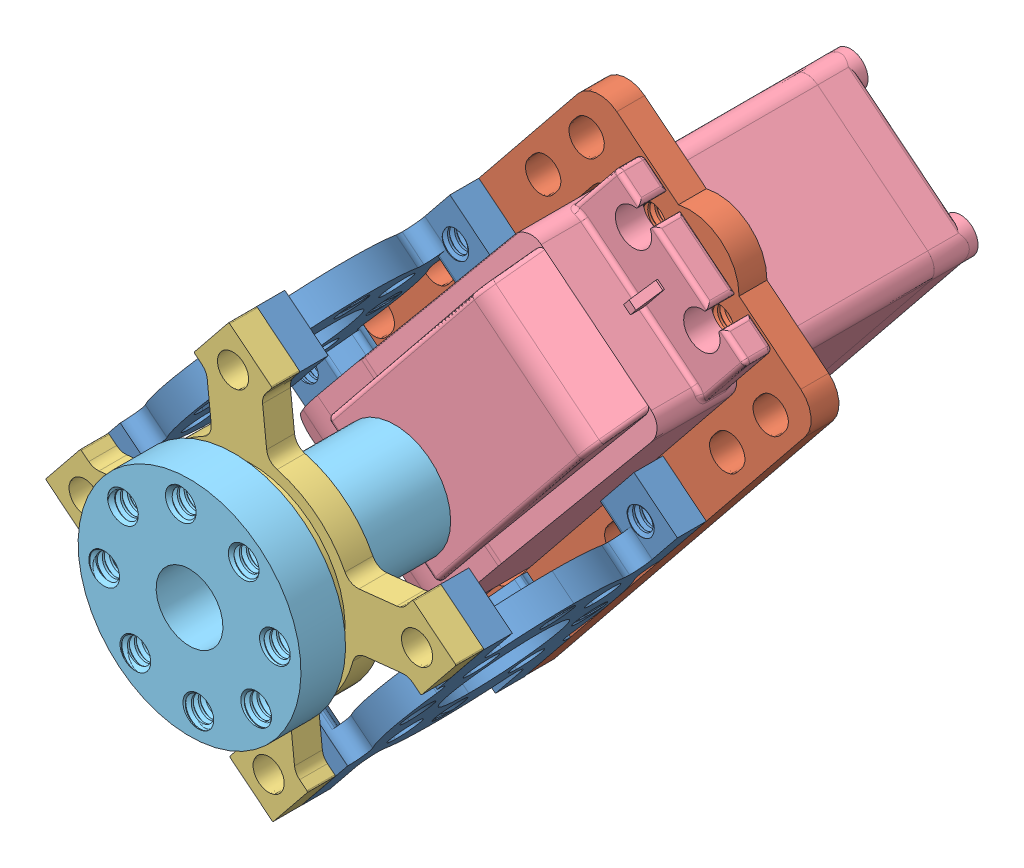
SolidWorks assembly Servo block subassembly, configuration Default. Lengths in mm.
Overall size (64.34 68.55 64.02).
6 component instances, 5 part files, 14 mates.
Components (placement in the parent):
- Side Tapped Pattern Mount A - 545420-1: Side Tapped Pattern Mount A - 545420 [Default] at (442.7678 380.2783 15.875) x (0 0 1) z (0.62777 0.778399 0) size (25.41 6.35 33.02)
- Standard Servo Plate A (575112)-1: Standard Servo Plate A (575112) [Default] at (461.4653 376.9471 0) x (-0.62777 -0.778399 0) z (-0.778399 0.62777 0) size (61.21 3.38 33.29)
- Side Tapped Pattern Mount A - 545420-2: Side Tapped Pattern Mount A - 545420 [Default] at (468.6812 359.3794 15.875) x (0 0 1) z (-0.62777 -0.778399 0) size (25.41 6.35 33.02)
- .5in pillow block-1: .5in pillow block [Default] at (481.7983 354.6785 13.937) x (-0.62777 -0.778399 0) z (-0.778399 0.62777 0) size (33.27 5.09 33.27)
- Servo 20kg elbow and gripper-1: Servo 20kg elbow and gripper [Default] at (462.0715 377.6239 -25.175) x (-0.62777 -0.778399 0) z (-0.778399 0.62777 0) size (55.1 45.65 20.12)
- Servo Hub Shafts 25T (525123)-1: Servo Hub Shafts 25T (525123) [Default] at (455.7245 369.8288 38.735) x (0.99476 0.102238 0) z (-0.102238 0.99476 0) size (25.39 25.51 25.39)
Mates (geometry in assembly coordinates):
- Coincident96: coincident anti-aligned: plane of Side Tapped Pattern Mount A - 545420-1 through (433.3188 387.8988 593.2399) normal (0 0 -1); plane of Standard Servo Plate A (575112)-1 through (441.6486 361.5348 568.1738) normal (0 0 1)
- Concentric109: concentric anti-aligned: circle of Side Tapped Pattern Mount A - 545420-1; cylinder of Standard Servo Plate A (575112)-1 through (433.8788 373.3581 568.2732) axis (0 0 -1) radius 1.778
- Concentric114: concentric anti-aligned: circle of Side Tapped Pattern Mount A - 545420-1; cylinder of .5in pillow block-1 through (453.6955 388.7705 621.8149) axis (0 0 1) radius 1.778
- Coincident101: coincident anti-aligned: plane of Standard Servo Plate A (575112)-1 through (441.6486 361.5348 568.1738) normal (0 0 1); plane of Side Tapped Pattern Mount A - 545420-2 through (478.1302 351.7589 593.2399) normal (0 0 -1)
- Concentric113: concentric aligned: circle of Standard Servo Plate A (575112)-1; circle of Side Tapped Pattern Mount A - 545420-2
- Parallel17: parallel aligned: plane of Standard Servo Plate A (575112)-1 through (454.6047 351.0858 568.1738) normal (0.778399 -0.62777 0); plane of Side Tapped Pattern Mount A - 545420-2 through (468.6812 359.3794 605.9399) normal (0.778399 -0.62777 0)
- Coincident104: coincident anti-aligned: plane of Servo 20kg elbow and gripper-1 through (442.4538 361.2638 593.2399) normal (0 0 -1); plane of Standard Servo Plate A (575112)-1 through (441.6486 361.5348 568.1738) normal (0 0 1)
- Concentric116: concentric anti-aligned: circle of Standard Servo Plate A (575112)-1; cylinder of Servo 20kg elbow and gripper-1 through (442.4538 361.2638 593.2399) axis (0 0 1) radius 2.075
- Parallel18: parallel aligned: plane of Standard Servo Plate A (575112)-1 through (454.6047 351.0858 568.1738) normal (0.778399 -0.62777 0); plane of Servo 20kg elbow and gripper-1 through (457.3076 355.7079 605.3899) normal (0.778399 -0.62777 0)
- Coincident103: coincident anti-aligned: plane of Side Tapped Pattern Mount A - 545420-2 through (478.1302 351.7589 618.6399) normal (0 0 1); plane of .5in pillow block-1 through (455.7245 369.8288 618.6399) normal (0 0 -1)
- Concentric115: concentric anti-aligned: circle of Side Tapped Pattern Mount A - 545420-2; circle of .5in pillow block-1
- Concentric119: concentric anti-aligned: cylinder of .5in pillow block-1 through (455.7245 369.8288 623.7263) axis (0 0 -1) radius 6.35; circle of Servo Hub Shafts 25T (525123)-1
- Coincident106: coincident anti-aligned: plane of .5in pillow block-1 through (455.7245 369.8288 623.7199) normal (0 0 1); plane of Servo Hub Shafts 25T (525123)-1 through (455.7245 369.8288 623.7199) normal (0 0 -1)
- Coincident107: coincident: plane of Standard Servo Plate A (575112)-1 through (461.4653 376.9471 0) normal (0 0 -1)
